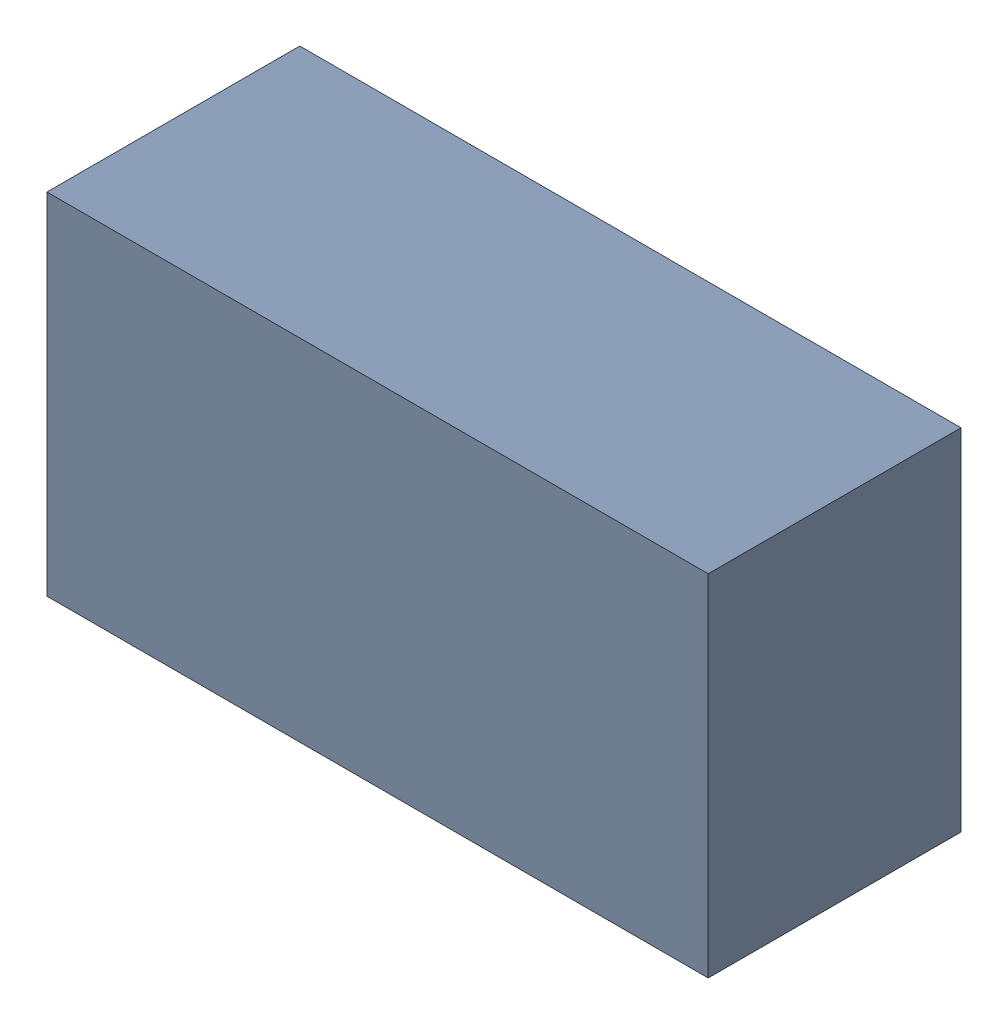
SolidWorks assembly C100, configuration Standard. Lengths in mm.
Overall size (3.4 1.8 1.3).
2 component instances, 1 part files, 0 mates.
Components (placement in the parent):
- 885542104-1: 885542104 [Standard] at (-12.065 24.21 0) size (3.4 1.8 1.3)
  - Extruded_29-1: Extruded_29 [Standard] at origin size (3.4 1.8 1.3)
